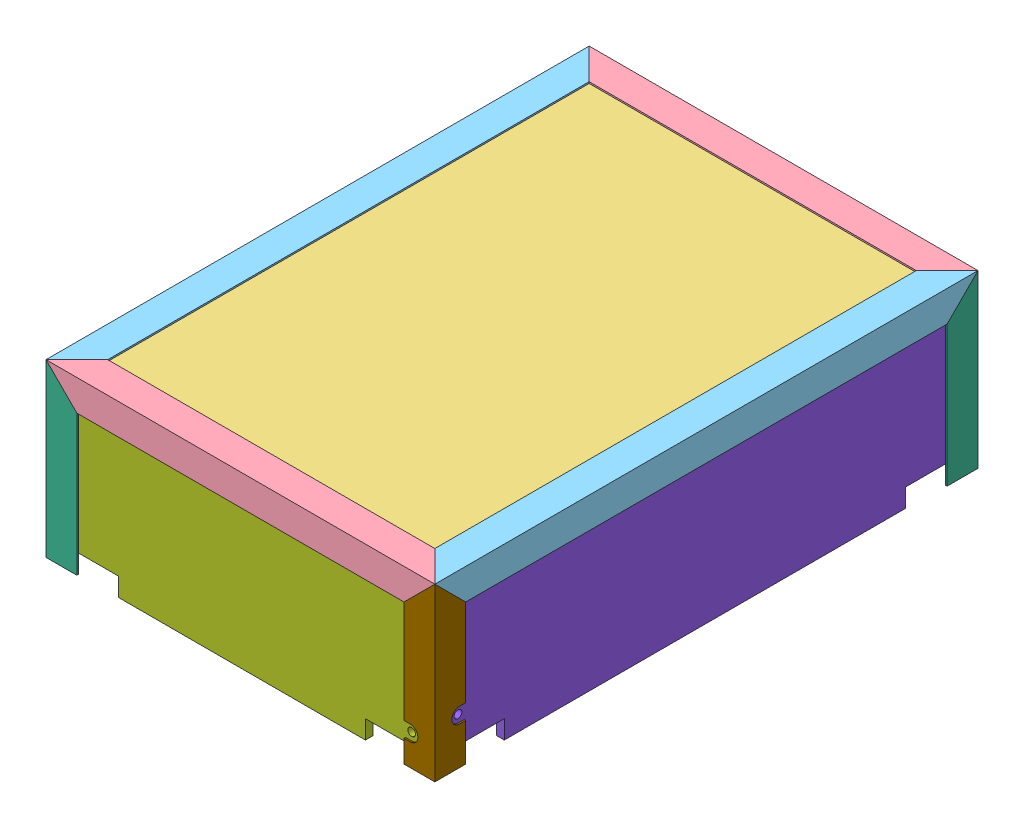
SolidWorks assembly couvercle, configuration Défaut. Lengths in mm.
Overall size (504 222 704).
13 component instances, 9 part files, 31 mates.
Components (placement in the parent):
- plaque_acrylique_680x210-2: plaque_acrylique_680x210 [Défaut] at (-487.4996 -8.7215 -345) x (0 0 -1) z (1 0 0) size (680 210 10)
- plaque_acrylique_380x210-2: plaque_acrylique_380x210 [Défaut] at (-187.4996 -8.7215 -695) size (480 210 10)
- plaque_acrylique_380x680-1: plaque_acrylique_380x680 [Défaut] at (-187.4996 96.2785 -345) x (1 0 0) z (0 1 0) size (480 680 10)
- eclisse_40x40x404_bisote_x2-1: eclisse_40x40x404_bisote_x2 [Défaut] at (14.5004 88.1649 -677) x (0 0 1) z (0 -1 0) size (40 504 40)
- eclisse_40x40x704_bisote_x2-1: eclisse_40x40x704_bisote_x2 [Défaut] at (-5.6132 88.2785 -697) x (0 -1 0) z (-1 0 0) size (40 704 40)
- eclisse_40x40x404_bisote_x2-2: eclisse_40x40x404_bisote_x2 [Défaut] at (-489.4996 88.1649 -13) x (0 0 -1) z (0 -1 0) size (40 504 40)
- eclisse_40x40x704_bisote_x2-2: eclisse_40x40x704_bisote_x2 [Défaut] at (-469.4996 88.1649 -697) x (1 0 0) z (0 -1 0) size (40 704 40)
- eclisse_40x40x222_bisote_x1-1: eclisse_40x40x222_bisote_x1 [Défaut] at (-469.386 108.2785 -677) x (0 0 1) z (1 0 0) size (40 222 40)
- eclisse_40x40x222_bisote_x1-2: eclisse_40x40x222_bisote_x1 [Défaut] at (-5.4996 108.2785 -676.8864) x (-1 0 0) z (0 0 1) size (40 222 40)
- eclisse_40x40x222_bisote_x1-4: eclisse_40x40x222_bisote_x1 [Défaut] at (-469.4996 108.2785 -13.1136) x (1 0 0) z (0 0 -1) size (40 222 40)
- plaque_acrylique_380x210_Moteur-1: plaque_acrylique_380x210_Moteur [Défaut] at (-187.4996 -8.7215 -5) size (480 210 10)
- plaque_acrylique_680x210_Moteur-1: plaque_acrylique_680x210_Moteur [Défaut] at (2.5004 -8.7215 -345) x (0 0 -1) z (1 0 0) size (680 210 10)
- eclisse_40x40x222_bisote_x1_Moteur-1: eclisse_40x40x222_bisote_x1_Moteur [Défaut] at (-5.6132 108.2785 -13) x (0 0 -1) z (-1 0 0) size (40 222 40)
Mates (geometry in assembly coordinates):
- Coïncidente5: coincident anti-aligned: plane of plaque_acrylique_680x210-2 through (-477.4996 -8.7215 -345) normal (1 0 0); plane of plaque_acrylique_380x210-2 through (-477.4996 96.2785 -685) normal (-1 0 0)
- Coïncidente6: coincident anti-aligned: plane of plaque_acrylique_680x210-2 through (-477.4996 96.2785 -685) normal (0 0 -1); plane of plaque_acrylique_380x210-2 through (-187.4996 -8.7215 -685) normal (0 0 1)
- Coïncidente12: coincident anti-aligned: plane of plaque_acrylique_680x210-2 through (-477.4996 96.2785 -5) normal (0 1 0); plane of plaque_acrylique_380x680-1 through (-187.4996 96.2785 -345) normal (0 -1 0)
- Coïncidente14: coincident anti-aligned: plane of plaque_acrylique_380x210-2 through (-187.4996 -8.7215 -685) normal (0 0 1); plane of plaque_acrylique_380x680-1 through (-477.4996 106.2785 -685) normal (0 0 -1)
- Coïncidente15: coincident anti-aligned: plane of plaque_acrylique_380x680-1 through (-187.4996 106.2785 -345) normal (0 1 0); plane of eclisse_40x40x704_bisote_x2-2 through (-487.4996 106.2785 7) normal (0 -1 0)
- Coïncidente16: coincident anti-aligned: plane of plaque_acrylique_380x680-1 through (-187.4996 106.2785 -345) normal (0 1 0); plane of eclisse_40x40x704_bisote_x2-1 through (12.5004 106.2785 7) normal (0 -1 0)
- Coïncidente18: coincident anti-aligned: plane of plaque_acrylique_680x210-2 through (-487.4996 -8.7215 -345) normal (-1 0 0); plane of eclisse_40x40x704_bisote_x2-2 through (-487.4996 106.2785 7) normal (1 0 0)
- Coïncidente19: coincident anti-aligned: plane of plaque_acrylique_380x680-1 through (-187.4996 106.2785 -345) normal (0 1 0); plane of eclisse_40x40x404_bisote_x2-2 through (14.5004 106.2785 5) normal (0 -1 0)
- Coïncidente21: coincident anti-aligned: plane of plaque_acrylique_380x680-1 through (-187.4996 106.2785 -345) normal (0 1 0); plane of eclisse_40x40x404_bisote_x2-1 through (-489.4996 106.2785 -695) normal (0 -1 0)
- Coïncidente22: coincident anti-aligned: plane of plaque_acrylique_380x210-2 through (-187.4996 -8.7215 -695) normal (0 0 -1); plane of eclisse_40x40x404_bisote_x2-1 through (-489.4996 106.2785 -695) normal (0 0 1)
- Coïncidente25: coincident anti-aligned: plane of eclisse_40x40x404_bisote_x2-1 through (-489.4996 68.2785 -697) normal (-0.707107 0 0.707107); plane of eclisse_40x40x704_bisote_x2-2 through (-489.4996 -481.7215 -697) normal (0.707107 0 -0.707107)
- Coïncidente28: coincident: point of eclisse_40x40x404_bisote_x2-1; point of eclisse_40x40x704_bisote_x2-2
- Coïncidente29: coincident anti-aligned: plane of eclisse_40x40x404_bisote_x2-1 through (14.5004 -481.7215 -697) normal (0.707107 0 0.707107); plane of eclisse_40x40x704_bisote_x2-1 through (14.5004 -481.7215 -697) normal (-0.707107 0 -0.707107)
- Coïncidente30: coincident anti-aligned: plane of eclisse_40x40x704_bisote_x2-1 through (14.5004 68.2785 7) normal (-0.707107 0 0.707107); plane of eclisse_40x40x404_bisote_x2-2 through (14.5004 68.2785 7) normal (0.707107 0 -0.707107)
- Coïncidente31: coincident anti-aligned: plane of eclisse_40x40x704_bisote_x2-2 through (100.5004 108.2785 -697) normal (0 -0.707107 -0.707107); plane of eclisse_40x40x222_bisote_x1-1 through (100.5004 108.2785 -697) normal (0 0.707107 0.707107)
- Coïncidente33: coincident aligned: plane of eclisse_40x40x404_bisote_x2-1 through (-489.4996 108.2785 -697) normal (0 0 -1); plane of eclisse_40x40x222_bisote_x1-1 through (-489.4996 -113.7215 -697) normal (0 0 -1)
- Coïncidente34: coincident anti-aligned: plane of eclisse_40x40x404_bisote_x2-1 through (-489.4996 108.2785 -657) normal (-0.707107 -0.707107 0); plane of eclisse_40x40x222_bisote_x1-1 through (-489.4996 108.2785 -107) normal (0.707107 0.707107 0)
- Coïncidente35: coincident aligned: plane of eclisse_40x40x404_bisote_x2-1 through (-489.4996 108.2785 -697) normal (0 0 -1); plane of eclisse_40x40x222_bisote_x1-2 through (14.5004 -113.7215 -697) normal (0 0 -1)
- Coïncidente36: coincident anti-aligned: plane of eclisse_40x40x404_bisote_x2-1 through (14.5004 108.2785 -107) normal (0.707107 -0.707107 0); plane of eclisse_40x40x222_bisote_x1-2 through (14.5004 108.2785 -107) normal (-0.707107 0.707107 0)
- Coïncidente37: coincident aligned: plane of eclisse_40x40x704_bisote_x2-1 through (14.5004 108.2785 7) normal (1 0 0); plane of eclisse_40x40x222_bisote_x1-2 through (14.5004 -113.7215 -697) normal (1 0 0)
- Coïncidente41: coincident aligned: plane of eclisse_40x40x704_bisote_x2-2 through (-489.4996 108.2785 7) normal (-1 0 0); plane of eclisse_40x40x222_bisote_x1-4 through (-489.4996 -113.7215 7) normal (-1 0 0)
- Coïncidente42: coincident anti-aligned: plane of eclisse_40x40x704_bisote_x2-2 through (-449.4996 108.2785 7) normal (0 -0.707107 0.707107); plane of eclisse_40x40x222_bisote_x1-4 through (100.5004 108.2785 7) normal (0 0.707107 -0.707107)
- Coïncidente43: coincident aligned: plane of eclisse_40x40x404_bisote_x2-2 through (14.5004 108.2785 7) normal (0 0 1); plane of eclisse_40x40x222_bisote_x1-4 through (-489.4996 -113.7215 7) normal (0 0 1)
- Coïncidente45: coincident anti-aligned: plane of plaque_acrylique_380x680-1 through (-187.4996 96.2785 -345) normal (0 -1 0); plane of plaque_acrylique_380x210_Moteur-1 through (-477.4996 96.2785 5) normal (0 1 0)
- Coïncidente46: coincident aligned: line of plaque_acrylique_680x210-2 through (-477.4996 96.2785 -5) axis (0 -1 0); line of plaque_acrylique_380x210_Moteur-1 through (-477.4996 96.2785 -5) axis (0 -1 0)
- Coïncidente47: coincident anti-aligned: plane of eclisse_40x40x222_bisote_x1-2 through (12.5004 -113.7215 -695) normal (-1 0 0); plane of plaque_acrylique_680x210_Moteur-1 through (12.5004 -8.7215 -345) normal (1 0 0)
- Coïncidente48: coincident anti-aligned: plane of plaque_acrylique_380x680-1 through (-187.4996 96.2785 -345) normal (0 -1 0); plane of plaque_acrylique_680x210_Moteur-1 through (12.5004 96.2785 -5) normal (0 1 0)
- Coïncidente49: coincident anti-aligned: line of plaque_acrylique_380x210_Moteur-1 through (2.5004 -89.7215 -5) axis (0 1 0); line of plaque_acrylique_680x210_Moteur-1 through (2.5004 96.2785 -5) axis (0 -1 0)
- Coïncidente53: coincident anti-aligned: plane of plaque_acrylique_680x210_Moteur-1 through (12.5004 -8.7215 -345) normal (1 0 0); plane of eclisse_40x40x222_bisote_x1_Moteur-1 through (12.5004 -113.7215 5) normal (-1 0 0)
- Coïncidente54: coincident anti-aligned: plane of plaque_acrylique_380x210_Moteur-1 through (-187.4996 -8.7215 5) normal (0 0 1); plane of eclisse_40x40x222_bisote_x1_Moteur-1 through (12.5004 -113.7215 5) normal (0 0 -1)
- Coïncidente55: coincident anti-aligned: plane of eclisse_40x40x404_bisote_x2-2 through (14.5004 108.2785 -33) normal (0.707107 -0.707107 0); plane of eclisse_40x40x222_bisote_x1_Moteur-1 through (14.5004 108.2785 -583) normal (-0.707107 0.707107 0)
